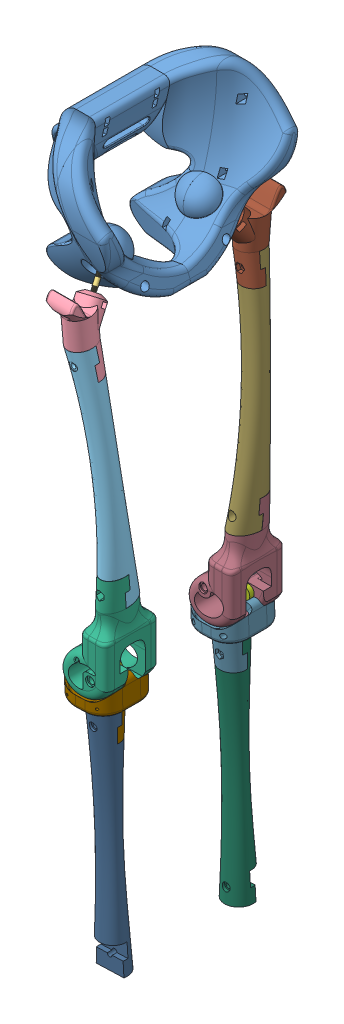
SolidWorks assembly 09_BA_001, configuration Default. Lengths in mm.
Overall size (197.88 962.11 294.61).
19 component instances, 15 part files, 49 mates.
Components (placement in the parent):
- 02_01_PE_001-1: 02_01_PE_001 [Default] at origin size (197.88 220.17 282.18)
- 6630T310_METRIC BLACK POLYPROPYLENE BALL KNOB-1: 6630T310_METRIC BLACK POLYPROPYLENE BALL KNOB [6630T31] at (-58.671 -58.8069 72.4936) x (0.804974 0.48308 0.344458) z (-0.194905 0.763657 -0.6155) size (38 38 37.9)
- 92997A108_CORROSION-RESISTANT SETUP STUD-1: 92997A108_CORROSION-RESISTANT SETUP STUD [92997A108] at (-55.0653 -72.9345 83.8804) x (0.017759 0.630179 0.776247) z (0.194905 -0.763657 0.6155) size (6.34 6.15 50.8)
- 03_02_FH_R_001-1: 03_02_FH_R_001 [Default] at (-45.3395 -121.5667 106.123) x (1 0 0) z (0 -0.087156 0.996195) size (46.92 105.86 63.35)
- 03_01_FB_R_001-1: 03_01_FB_R_001 [Default] at (-44.1058 -425.8587 87.0078) x (1 0 0) z (0 -0.087156 0.996195) size (54.81 304.92 50.87)
- 04_01_KT_R_001-1: 04_01_KT_R_001 [Default] at (-35.6321 -504.5163 84.7583) size (77.01 157.24 74.14)
- 04_05_BL_001-1: 04_05_BL_001 [Default] at (-42.5577 -521.5571 84.8583) x (0.712112 0.702066 0) z (0 0 1) size (62.75 16 5.9)
- 04_06_FL_001-1: 04_06_FL_001 [Default] at (-31.6099 -512.6089 78.7583) x (0.469804 -0.882771 0) z (0 0 1) size (67.43 16 5.9)
- 04_02_KB_R_001-1: 04_02_KB_R_001 [Default] at (-43.0474 -546.2764 84.7583) x (0.999391 0.034899 0) z (0 0 1) size (78.49 85.12 75.75)
- 05_01_TI_R_001-1: 05_01_TI_R_001 [Default] at (-42.6984 -556.2703 84.7583) x (0.999391 0.034899 0) z (0 0 1) size (38.19 304.9 38.19)
- 6630T310_METRIC BLACK POLYPROPYLENE BALL KNOB-2: 6630T310_METRIC BLACK POLYPROPYLENE BALL KNOB [6630T31] at (-58.671 -58.8069 -72.4936) x (0.963134 0.030376 0.2673) z (-0.194905 0.763657 0.6155) size (38 38 37.9)
- 92997A108_CORROSION-RESISTANT SETUP STUD-2: 92997A108_CORROSION-RESISTANT SETUP STUD [92997A108] at (-55.0653 -72.9345 -83.8804) x (-0.54916 -0.604916 0.576628) z (-0.194905 0.763657 0.6155) size (6.34 6.15 50.8)
- 03_04_FH_L_001-1: 03_04_FH_L_001 [Default] at (-45.3395 -121.5667 -106.123) x (1 0 0) z (0 0.087156 0.996195) size (46.92 105.86 63.35)
- 03_03_FB_L_001-1: 03_03_FB_L_001 [Default] at (-44.1058 -425.8587 -87.0078) x (1 0 0) z (0 0.087156 0.996195) size (54.81 304.92 50.87)
- 04_03_KT_L_001-1: 04_03_KT_L_001 [Default] at (-35.6321 -504.5163 -84.7583) size (77.01 157.24 74.14)
- 04_05_BL_001-2: 04_05_BL_001 [Default] at (-42.5577 -521.5571 -90.7583) x (0.712112 0.702066 0) z (0 0 1) size (62.75 16 5.9)
- 04_06_FL_001-2: 04_06_FL_001 [Default] at (-31.6099 -512.6089 -84.6583) x (-0.469804 0.882771 0) z (0 0 1) size (67.43 16 5.9)
- 04_04_KB_L_001-1: 04_04_KB_L_001 [Default] at (-43.0474 -546.2764 -84.8583) x (0.999391 0.034899 0) z (0 0 1) size (78.49 85.12 75.75)
- 05_02_TI_001-1: 05_02_TI_001 [Default] at (-42.6984 -556.2703 -84.8583) x (0.999391 0.034899 0) z (0 0 1) size (38.19 304.9 38.19)
Mates (geometry in assembly coordinates):
- Concentric1: concentric: sphere of 02_01_Pelvis-1; sphere of 6630T310_METRIC BLACK POLYPROPYLENE BALL KNOB-1
- Concentric2: concentric aligned: circle of 6630T310_METRIC BLACK POLYPROPYLENE BALL KNOB-1; cylinder of 92997A108_CORROSION-RESISTANT SETUP STUD-1 through (-50.1927 -92.0259 99.2679) axis (0.194905 -0.763657 0.6155) radius 3.02
- Coincident1: coincident anti-aligned: plane of 6630T310_METRIC BLACK POLYPROPYLENE BALL KNOB-1 through (-59.9379 -53.8431 68.4929) normal (0.194905 -0.763657 0.6155); plane of 92997A108_CORROSION-RESISTANT SETUP STUD-1 through (-59.9379 -53.8431 68.4929) normal (-0.194905 0.763657 -0.6155)
- Concentric3: concentric anti-aligned: cylinder of 92997A108_CORROSION-RESISTANT SETUP STUD-1 through (-50.1927 -92.0259 99.2679) axis (0.194905 -0.763657 0.6155) radius 3.02; cylinder of 03_02_FemurHead_Right-1 through (-50.1927 -92.0259 99.2679) axis (-0.194905 0.763657 -0.6155) radius 3.125
- Coincident2: coincident anti-aligned: plane of 92997A108_CORROSION-RESISTANT SETUP STUD-1 through (-50.1927 -92.0259 99.2679) normal (0.194905 -0.763657 0.6155); plane of 03_02_FemurHead_Right-1 through (-50.1927 -92.0259 99.2679) normal (-0.194905 0.763657 -0.6155)
- Coincident3: coincident anti-aligned: plane of 03_02_FemurHead_Right-1 through (-6.4724 -121.8919 109.8397) normal (0 -0.087156 0.996195); plane of 03_01_FemurBone_Right-1 through (-6.4656 -425.532 83.2746) normal (0 0.087156 -0.996195)
- Coincident4: coincident anti-aligned: plane of 03_02_FemurHead_Right-1 through (-45.3395 -122.2223 113.6156) normal (0 -0.996195 -0.087156); plane of 03_01_FemurBone_Right-1 through (-45.3394 -122.2223 113.6157) normal (0 0.996195 0.087156)
- Concentric4: concentric aligned: cylinder of 03_02_FemurHead_Right-1 through (-41.8015 -143.6299 139.7315) axis (0 0.087156 -0.996195) radius 3.175; cylinder of 03_01_FemurBone_Right-1 through (-41.8015 -143.4149 137.2744) axis (0 0.087156 -0.996195) radius 3.175
- Coincident5: coincident anti-aligned: plane of 03_01_FemurBone_Right-1 through (-6.4656 -425.6763 84.9233) normal (0 -0.087156 0.996195); plane of 04_01_KneeTop_Right-1 through (-0.2749 -503.9317 78.0769) normal (0 0.087156 -0.996195)
- Coincident6: coincident anti-aligned: plane of 03_01_FemurBone_Right-1 through (-6.4656 -387.9074 90.3712) normal (0 -0.996195 -0.087156); plane of 04_01_KneeTop_Right-1 through (-0.2749 -388.3058 94.9254) normal (0 0.996195 0.087156)
- Concentric5: concentric anti-aligned: cylinder of 03_01_FemurBone_Right-1 through (-23.6321 -409.1 114.0299) axis (0 0.087156 -0.996195) radius 3.175; cylinder of 04_01_KneeTop_Right-1 through (-23.6321 -403.1666 46.2101) axis (0 -0.087156 0.996195) radius 3.25
- Concentric6: concentric aligned: cylinder of 04_01_KneeTop_Right-1 through (-25.9121 -505.1463 121.7583) axis (0 0 -1) radius 3; cylinder of 04_05_BackLink-1 through (-25.9121 -505.1463 90.7583) axis (0 0 -1) radius 3.15
- Coincident7: coincident anti-aligned: plane of 04_01_KneeTop_Right-1 through (-67.8349 -532.8861 90.7583) normal (0 0 -1); plane of 04_05_BackLink-1 through (-25.9121 -505.1463 90.7583) normal (0 0 1)
- Concentric7: concentric anti-aligned: cylinder of 04_01_KneeTop_Right-1 through (-43.6921 -489.9063 47.7583) axis (0 0 1) radius 3; cylinder of 04_06_FrontLink-1 through (-43.6921 -489.9063 84.6583) axis (0 0 -1) radius 3.15
- Coincident8: coincident anti-aligned: plane of 04_01_KneeTop_Right-1 through (-67.8349 -532.8861 78.7583) normal (0 0 1); plane of 04_06_FrontLink-1 through (-19.5277 -535.3116 78.7583) normal (0 0 -1)
- Concentric8: concentric anti-aligned: cylinder of 04_05_BackLink-1 through (-59.2033 -537.9679 90.7583) axis (0 0 -1) radius 3.15; cylinder of 04_02_KneeBottom_Right-1 through (-59.2033 -537.9679 69.7583) axis (0 0 1) radius 3.1
- Coincident9: coincident anti-aligned: plane of 04_05_BackLink-1 through (-25.9121 -505.1463 90.7583) normal (0 0 1); plane of 04_02_KneeBottom_Right-1 through (-34.8274 -504.104 90.7583) normal (0 0 -1)
- Concentric9: concentric anti-aligned: cylinder of 04_06_FrontLink-1 through (-19.5277 -535.3116 84.6583) axis (0 0 -1) radius 3.15; cylinder of 04_02_KneeBottom_Right-1 through (-19.5277 -535.3116 69.7583) axis (0 0 1) radius 3.1
- LimitAngle1: limit planar angle = 0.034907 rad aligned: plane of 04_02_KneeBottom_Right-1 through (-7.9656 -505.0269 122.2583) normal (0.999391 0.034899 0); plane of 04_01_KneeTop_Right-1 through (-5.6321 -455.7765 121.7583) normal (1 0 0)
- Coincident11: coincident anti-aligned: plane of 04_02_KneeBottom_Right-1 through (-82.9466 -547.6697 80.8456) normal (0 0 1); plane of 05_01_Tibial_Right-1 through (-61.7832 -556.9367 80.8456) normal (0 0 -1)
- Coincident12: coincident anti-aligned: plane of 04_02_KneeBottom_Right-1 through (-82.5976 -557.6636 84.7583) normal (0.034899 -0.999391 0); plane of 05_01_Tibial_Right-1 through (-42.6984 -556.2703 84.7583) normal (-0.034899 0.999391 0)
- Concentric10: concentric aligned: cylinder of 04_02_KneeBottom_Right-1 through (-41.8513 -575.3023 46.8849) axis (0 0 1) radius 3.25; cylinder of 05_01_Tibial_Right-1 through (-41.8513 -575.3023 65.6619) axis (0 0 1) radius 3.25
- Concentric11: concentric: sphere of 02_01_Pelvis-1; sphere of 6630T310_METRIC BLACK POLYPROPYLENE BALL KNOB-2
- Concentric12: concentric anti-aligned: circle of 6630T310_METRIC BLACK POLYPROPYLENE BALL KNOB-2; cylinder of 92997A108_CORROSION-RESISTANT SETUP STUD-2 through (-59.9379 -53.8431 -68.4929) axis (-0.194905 0.763657 0.6155) radius 3.02
- Coincident13: coincident anti-aligned: plane of 6630T310_METRIC BLACK POLYPROPYLENE BALL KNOB-2 through (-59.9379 -53.8431 -68.4929) normal (0.194905 -0.763657 -0.6155); plane of 92997A108_CORROSION-RESISTANT SETUP STUD-2 through (-59.9379 -53.8431 -68.4929) normal (-0.194905 0.763657 0.6155)
- Concentric13: concentric aligned: cylinder of 92997A108_CORROSION-RESISTANT SETUP STUD-2 through (-59.9379 -53.8431 -68.4929) axis (-0.194905 0.763657 0.6155) radius 3.02; cylinder of 03_04_FemurHead_Left-1 through (-50.1927 -92.0259 -99.2679) axis (-0.194905 0.763657 0.6155) radius 3.125
- Coincident14: coincident anti-aligned: plane of 92997A108_CORROSION-RESISTANT SETUP STUD-2 through (-50.1927 -92.0259 -99.2679) normal (0.194905 -0.763657 -0.6155); plane of 03_04_FemurHead_Left-1 through (-50.1927 -92.0259 -99.2679) normal (-0.194905 0.763657 0.6155)
- Coincident15: coincident anti-aligned: plane of 03_04_FemurHead_Left-1 through (-6.4724 -121.8919 -109.8397) normal (0 -0.087156 -0.996195); plane of 03_03_FemurBone_Left-1 through (-6.4656 -425.532 -83.2746) normal (0 0.087156 0.996195)
- Coincident16: coincident anti-aligned: plane of 03_04_FemurHead_Left-1 through (-45.3395 -122.2223 -113.6156) normal (0 -0.996195 0.087156); plane of 03_03_FemurBone_Left-1 through (-45.3394 -122.2223 -113.6157) normal (0 0.996195 -0.087156)
- Concentric14: concentric aligned: cylinder of 03_04_FemurHead_Left-1 through (-41.8015 -143.6299 -139.7315) axis (0 0.087156 0.996195) radius 3.175; cylinder of 03_03_FemurBone_Left-1 through (-41.8015 -143.4149 -137.2744) axis (0 0.087156 0.996195) radius 3.175
- Coincident17: coincident anti-aligned: plane of 03_03_FemurBone_Left-1 through (-6.4656 -425.6763 -84.9233) normal (0 -0.087156 -0.996195); plane of 04_03_KneeTop_Left-1 through (-0.2749 -503.9317 -78.0769) normal (0 0.087156 0.996195)
- Coincident18: coincident anti-aligned: plane of 03_03_FemurBone_Left-1 through (-6.4656 -387.9074 -90.3712) normal (0 -0.996195 0.087156); plane of 04_03_KneeTop_Left-1 through (-0.2749 -388.3058 -94.9254) normal (0 0.996195 -0.087156)
- Concentric15: concentric anti-aligned: cylinder of 03_03_FemurBone_Left-1 through (-23.6321 -409.1 -114.0299) axis (0 0.087156 0.996195) radius 3.175; cylinder of 04_03_KneeTop_Left-1 through (-23.6321 -403.1666 -46.2101) axis (0 -0.087156 -0.996195) radius 3.25
- Concentric16: concentric anti-aligned: cylinder of 04_03_KneeTop_Left-1 through (-25.9121 -505.1463 -121.7583) axis (0 0 1) radius 3; cylinder of 04_05_BackLink-2 through (-25.9121 -505.1463 -84.8583) axis (0 0 -1) radius 3.15
- Coincident19: coincident anti-aligned: plane of 04_03_KneeTop_Left-1 through (-67.8349 -532.8861 -90.7583) normal (0 0 1); plane of 04_05_BackLink-2 through (-25.9121 -505.1463 -90.7583) normal (0 0 -1)
- Concentric17: concentric aligned: cylinder of 04_03_KneeTop_Left-1 through (-43.6921 -489.9063 -47.7583) axis (0 0 -1) radius 3; cylinder of 04_06_FrontLink-2 through (-43.6921 -489.9063 -78.7583) axis (0 0 -1) radius 3.15
- Coincident20: coincident anti-aligned: plane of 04_03_KneeTop_Left-1 through (-67.8349 -532.8861 -78.7583) normal (0 0 -1); plane of 04_06_FrontLink-2 through (-43.6921 -489.9063 -78.7583) normal (0 0 1)
- Concentric18: concentric aligned: cylinder of 04_05_BackLink-2 through (-59.2033 -537.9679 -84.8583) axis (0 0 -1) radius 3.15; cylinder of 04_04_KneeBottom_Left-1 through (-59.2033 -537.9679 -46.9849) axis (0 0 -1) radius 3.2
- Coincident21: coincident anti-aligned: plane of 04_05_BackLink-2 through (-25.9121 -505.1463 -84.8583) normal (0 0 1); plane of 04_04_KneeBottom_Left-1 through (-59.2033 -537.9679 -84.8583) normal (0 0 -1)
- Concentric19: concentric aligned: cylinder of 04_06_FrontLink-2 through (-19.5277 -535.3116 -78.7583) axis (0 0 -1) radius 3.15; cylinder of 04_04_KneeBottom_Left-1 through (-19.5277 -535.3116 -46.9849) axis (0 0 -1) radius 3.2
- LimitAngle2: limit planar angle = 0.034907 rad aligned: plane of 04_03_KneeTop_Left-1 through (-5.6321 -455.7765 -121.7583) normal (1 0 0); plane of 04_04_KneeBottom_Left-1 through (-7.9656 -505.0269 -122.3583) normal (0.999391 0.034899 0)
- Coincident23: coincident anti-aligned: plane of 04_04_KneeBottom_Left-1 through (-82.9466 -547.6697 -80.9456) normal (0 0 -1); plane of 05_02_Tibial_Left-1 through (-61.7832 -556.9367 -80.9456) normal (0 0 1)
- Coincident24: coincident anti-aligned: plane of 04_04_KneeBottom_Left-1 through (-82.5976 -557.6636 -84.8583) normal (0.034899 -0.999391 0); plane of 05_02_Tibial_Left-1 through (-42.6984 -556.2703 -84.8583) normal (-0.034899 0.999391 0)
- Concentric20: concentric aligned: cylinder of 04_04_KneeBottom_Left-1 through (-41.8513 -575.3023 -46.9849) axis (0 0 -1) radius 3.25; cylinder of 05_02_Tibial_Left-1 through (-41.8513 -575.3023 -65.7619) axis (0 0 -1) radius 3.25
- Parallel6: parallel: plane of assembly through (0 0 0) normal (1 0 0); plane of 04_01_KneeTop_Right-1 through (-5.6321 -455.7765 121.7583) normal (1 0 0)
- Parallel7: parallel: plane of assembly through (0 0 0) normal (1 0 0); plane of 04_03_KneeTop_Left-1 through (-5.6321 -455.7765 -121.7583) normal (1 0 0)
- Parallel8: parallel aligned: 
- Parallel9: parallel: plane of assembly through (0 0 0) normal (0 0 1); plane of 04_01_KneeTop_Right-1 through (-35.6321 -504.5163 47.7583) normal (0 0 -1)
- Parallel10: parallel: plane of assembly through (0 0 0) normal (0 0 1); plane of 04_03_KneeTop_Left-1 through (-35.6321 -504.5163 -47.7583) normal (0 0 1)
